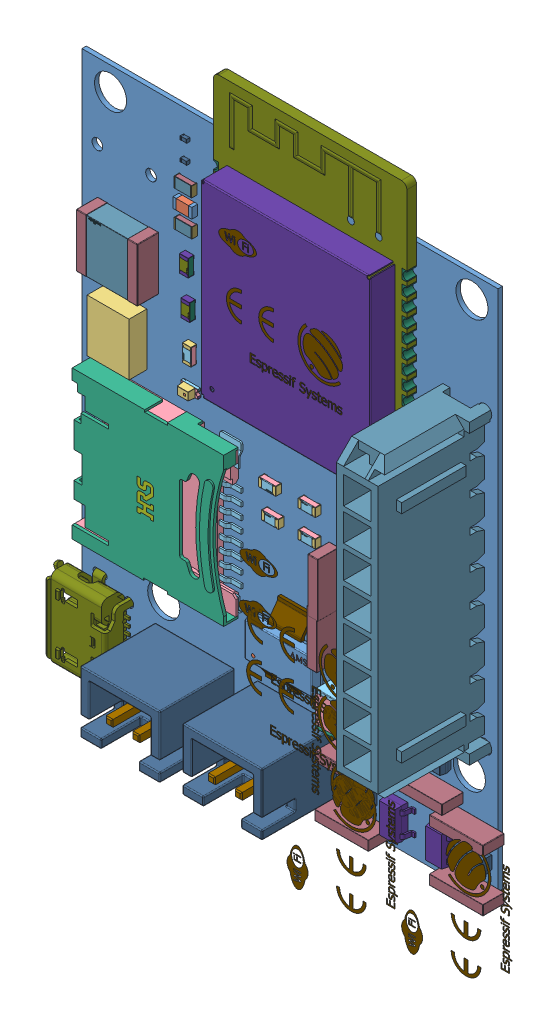
SolidWorks assembly PCB_F.step, configuration Default. Lengths in mm.
Overall size (45.18 58.57 13.33).
223 component instances, 63 part files, 0 mates.
Components (placement in the parent):
- Board.step-1: Board.step [Default] at origin size (38.73 49.78 0.41)
  - Open CASCADE STEP translator 7.5 1.1.1.step-1: Open CASCADE STEP translator 7.5 1.1.1.step [Default] at (0 0 -0.4115) size (38.73 49.78 0.41)
- D100.step-1: D100.step [Default] at origin size (1.6 0.8 0.9)
  - Diode_Lite-On_LTST-C190GKT_eec.step-1: Diode_Lite-On_LTST-C190GKT_eec.step [Default] at (150.229 50.673 0) x (-1 0 0) z (0 0 1) size (1.6 0.8 0.9)
    - 1.step-1: 1.step [Default] at (-0.1749 0.0038 0.001) size (0.2 0.2 0.05)
    - 2.step-1: 2.step [Default] at origin size (1.1 0.8 0.64)
    - 3.step-1: 3.step [Default] at origin size (1.6 0.8 0.28)
    - 4.step-1: 4.step [Default] at origin size (1.6 0.8 0.24)
    - Lite-On Logo Adjustable.step-1: Lite-On Logo Adjustable.step [Default] at (-0.9132 -0.3001 -1.9175) x (1 0 0) z (0 -1 0) size (0.21 0.05 0.1)
    - 5.step-1: 5.step [Default] at origin size (1.6 0.7 0.24)
    - 6.step-1: 6.step [Default] at origin size (1.6 0.15 0.24)
- J202.step-1: J202.step [Default] at origin size (7.4 5.75 10.4)
  - Conn_JST_B2B-XH-A_LF_SN_eec.step-1: Conn_JST_B2B-XH-A_LF_SN_eec.step [Default] at (160.02 27.305 0) x (-1 0 0) z (0 0 1) size (7.4 5.75 10.4)
    - 1-0.step-1: 1-0.step [Default] at (0 0.025 0) x (-1 0 0) z (0 1 0) size (7.4 10.4 5.75)
      - 1-1.step-1: 1-1.step [Default] at origin size (3.14 10.2 0.64)
      - B2B-XH-A.step-1: B2B-XH-A.step [Default] at origin size (7.4 7 5.75)
      - JST Logo adjustable.step-1: JST Logo adjustable.step [Default] at (-1.7267 5.5034 2.841) size (0.85 2.3 0.01)
- R103.step-1: R103.step [Default] at origin size (1.65 0.95 0.5)
  - 6298187712.step-1: 6298187712.step [Default] at (149.875 63.627 0) x (1 0 0) z (0 0 1) size (1.65 0.95 0.5)
    - Terminal.step-1: Terminal.step [Default] at (-0.825 -0.475 0) size (0.1 0.95 0.5)
      - Open CASCADE STEP translator 6.8 3.2.1.step-1: Open CASCADE STEP translator 6.8 3.2.1.step [Default] at origin size (0.1 0.95 0.5)
    - Terminal.step-2: Terminal.step [Default] at (0.825 0.475 0) x (-1 0 0) z (0 0 1) size (0.1 0.95 0.5)
      - Open CASCADE STEP translator 6.8 3.2.1.step-1: Open CASCADE STEP translator 6.8 3.2.1.step [Default] at origin size (0.1 0.95 0.5)
    - Mid_Body.step-1: Mid_Body.step [Default] at (-0.825 -0.475 0) size (1.55 0.95 0.4)
    - Mark.step-1: Mark.step [Default] at (-0.725 -0.475 0.45) size (1.45 0.95 0.05)
- R300.step-1: R300.step [Default] at origin size (1.6 0.8 0.56)
  - Res_Panasonic_Electronic_Components_ERA-3ARB202V_eec.step-1: Res_Panasonic_Electronic_Components_ERA-3ARB202V_eec.step [Default] at (165.9526 38.227 -0.4115) x (1 0 0) z (0 0 -1) size (1.6 0.8 0.56)
    - 1-2.step-1: 1-2.step [Default] at origin size (1.52 0.8 0.47)
    - 2-3.step-1: 2-3.step [Default] at origin size (1.08 0.8 0.04)
    - 3-4.step-1: 3-4.step [Default] at origin size (1.6 0.8 0.55)
    - Panasonic Logo.step-1: Panasonic Logo.step [Default] at (-0.1032 0.2046 0.451) size (0.41 0.06 0.11)
- R112.step-1: R112.step [Default] at origin size (1.75 0.95 0.55)
  - 6734516656.step-1: 6734516656.step [Default] at (149.135 65.278 0) size (0.3 0.95 0.55)
    - Extruded.step-1: Extruded.step [Default] at origin size (0.3 0.95 0.55)
  - 6734516656.step-2: 6734516656.step [Default] at (150.585 65.278 0) size (0.3 0.95 0.55)
    - Extruded.step-1: Extruded.step [Default] at origin size (0.3 0.95 0.55)
  - 6734516416.step-1: 6734516416.step [Default] at (149.86 65.278 0) size (1.15 0.95 0.55)
    - Extruded-5.step-1: Extruded-5.step [Default] at origin size (1.15 0.95 0.55)
- R111.step-1: R111.step [Default] at origin size (0.8 1.6 0.56)
  - Res_Panasonic_Electronic_Components_ERA-3ARB202V_eec.step-1: Res_Panasonic_Electronic_Components_ERA-3ARB202V_eec.step [Default] at (150.114 57.15 0) x (0 -1 0) z (0 0 1) size (1.6 0.8 0.56)
    - 1-2.step-1: 1-2.step [Default] at origin size (1.52 0.8 0.47)
    - 2-3.step-1: 2-3.step [Default] at origin size (1.08 0.8 0.04)
    - 3-4.step-1: 3-4.step [Default] at origin size (1.6 0.8 0.55)
    - Panasonic Logo.step-1: Panasonic Logo.step [Default] at (-0.1032 0.2046 0.451) size (0.41 0.06 0.11)
- R110.step-1: R110.step [Default] at origin size (0.8 1.6 0.56)
  - Res_Panasonic_Electronic_Components_ERA-3ARB202V_eec.step-1: Res_Panasonic_Electronic_Components_ERA-3ARB202V_eec.step [Default] at (149.987 60.6696 0) x (0 -1 0) z (0 0 1) size (1.6 0.8 0.56)
    - 1-2.step-1: 1-2.step [Default] at origin size (1.52 0.8 0.47)
    - 2-3.step-1: 2-3.step [Default] at origin size (1.08 0.8 0.04)
    - 3-4.step-1: 3-4.step [Default] at origin size (1.6 0.8 0.55)
    - Panasonic Logo.step-1: Panasonic Logo.step [Default] at (-0.1032 0.2046 0.451) size (0.41 0.06 0.11)
- R109.step-1: R109.step [Default] at origin size (1.6 0.8 0.56)
  - Res_Panasonic_ERJ-3GEYJ102V_eec.step-1: Res_Panasonic_ERJ-3GEYJ102V_eec.step [Default] at (157.988 44.196 0) x (1 0 0) z (0 0 1) size (1.6 0.8 0.56)
    - Pieza60.step-1: Pieza60.step [Default] at origin size (1.6 0.8 0.54)
    - Pieza63.step-1: Pieza63.step [Default] at (-0.65 -0.4 0.26) x (1 0 0) z (0 -1 0) size (1.5 0.44 0.8)
    - Pieza64.step-1: Pieza64.step [Default] at (0 -0.4 0.26) x (1 0 0) z (0 -1 0) size (1 0.06 0.8)
    - Pieza65.step-1: Pieza65.step [Default] at (-0.5 -0.4 0.55) x (-1 0 0) z (0 0 1) size (0.55 0.09 0.02)
- R108.step-1: R108.step [Default] at origin size (0.8 1.6 0.56)
  - Res_Panasonic_ERJ-3GEYJ102V_eec.step-1: Res_Panasonic_ERJ-3GEYJ102V_eec.step [Default] at (150.241 53.6051 0) x (0 1 0) z (0 0 1) size (1.6 0.8 0.56)
    - Pieza60.step-1: Pieza60.step [Default] at origin size (1.6 0.8 0.54)
    - Pieza63.step-1: Pieza63.step [Default] at (-0.65 -0.4 0.26) x (1 0 0) z (0 -1 0) size (1.5 0.44 0.8)
    - Pieza64.step-1: Pieza64.step [Default] at (0 -0.4 0.26) x (1 0 0) z (0 -1 0) size (1 0.06 0.8)
    - Pieza65.step-1: Pieza65.step [Default] at (-0.5 -0.4 0.55) x (-1 0 0) z (0 0 1) size (0.55 0.09 0.02)
- R107.step-1: R107.step [Default] at origin size (1.6 0.8 0.56)
  - Res_Panasonic_ERJ-3GEYJ102V_eec.step-1: Res_Panasonic_ERJ-3GEYJ102V_eec.step [Default] at (161.417 44.323 0) x (1 0 0) z (0 0 1) size (1.6 0.8 0.56)
    - Pieza60.step-1: Pieza60.step [Default] at origin size (1.6 0.8 0.54)
    - Pieza63.step-1: Pieza63.step [Default] at (-0.65 -0.4 0.26) x (1 0 0) z (0 -1 0) size (1.5 0.44 0.8)
    - Pieza64.step-1: Pieza64.step [Default] at (0 -0.4 0.26) x (1 0 0) z (0 -1 0) size (1 0.06 0.8)
    - Pieza65.step-1: Pieza65.step [Default] at (-0.5 -0.4 0.55) x (-1 0 0) z (0 0 1) size (0.55 0.09 0.02)
- R106.step-1: R106.step [Default] at origin size (1.6 0.8 0.56)
  - Res_Panasonic_ERJ-3GEYJ102V_eec.step-1: Res_Panasonic_ERJ-3GEYJ102V_eec.step [Default] at (161.417 46.863 0) x (1 0 0) z (0 0 1) size (1.6 0.8 0.56)
    - Pieza60.step-1: Pieza60.step [Default] at origin size (1.6 0.8 0.54)
    - Pieza63.step-1: Pieza63.step [Default] at (-0.65 -0.4 0.26) x (1 0 0) z (0 -1 0) size (1.5 0.44 0.8)
    - Pieza64.step-1: Pieza64.step [Default] at (0 -0.4 0.26) x (1 0 0) z (0 -1 0) size (1 0.06 0.8)
    - Pieza65.step-1: Pieza65.step [Default] at (-0.5 -0.4 0.55) x (-1 0 0) z (0 0 1) size (0.55 0.09 0.02)
- R105.step-1: R105.step [Default] at origin size (1.6 0.8 0.56)
  - Res_Panasonic_ERJ-3GEYJ102V_eec.step-1: Res_Panasonic_ERJ-3GEYJ102V_eec.step [Default] at (157.734 46.736 0) x (-1 0 0) z (0 0 1) size (1.6 0.8 0.56)
    - Pieza60.step-1: Pieza60.step [Default] at origin size (1.6 0.8 0.54)
    - Pieza63.step-1: Pieza63.step [Default] at (-0.65 -0.4 0.26) x (1 0 0) z (0 -1 0) size (1.5 0.44 0.8)
    - Pieza64.step-1: Pieza64.step [Default] at (0 -0.4 0.26) x (1 0 0) z (0 -1 0) size (1 0.06 0.8)
    - Pieza65.step-1: Pieza65.step [Default] at (-0.5 -0.4 0.55) x (-1 0 0) z (0 0 1) size (0.55 0.09 0.02)
- R104.step-1: R104.step [Default] at origin size (1.65 0.95 0.5)
  - 6298187712.step-1: 6298187712.step [Default] at (149.845 66.929 0) x (1 0 0) z (0 0 1) size (1.65 0.95 0.5)
    - Terminal.step-1: Terminal.step [Default] at (-0.825 -0.475 0) size (0.1 0.95 0.5)
      - Open CASCADE STEP translator 6.8 3.2.1.step-1: Open CASCADE STEP translator 6.8 3.2.1.step [Default] at origin size (0.1 0.95 0.5)
    - Terminal.step-2: Terminal.step [Default] at (0.825 0.475 0) x (-1 0 0) z (0 0 1) size (0.1 0.95 0.5)
      - Open CASCADE STEP translator 6.8 3.2.1.step-1: Open CASCADE STEP translator 6.8 3.2.1.step [Default] at origin size (0.1 0.95 0.5)
    - Mid_Body.step-1: Mid_Body.step [Default] at (-0.825 -0.475 0) size (1.55 0.95 0.4)
    - Mark.step-1: Mark.step [Default] at (-0.725 -0.475 0.45) size (1.45 0.95 0.05)
- R100.step-1: R100.step [Default] at origin size (1.65 0.95 0.5)
  - 6605284272.step-1: 6605284272.step [Default] at (169.784 48.641 0) x (-1 0 0) z (0 0 1) size (1.65 0.95 0.5)
    - Terminal-1.step-1: Terminal-1.step [Default] at (-0.825 -0.475 0) size (0.1 0.95 0.5)
      - Open CASCADE STEP translator 6.8 3.2.1-6.step-1: Open CASCADE STEP translator 6.8 3.2.1-6.step [Default] at origin size (0.1 0.95 0.5)
    - Terminal-1.step-2: Terminal-1.step [Default] at (0.825 0.475 0) x (-1 0 0) z (0 0 1) size (0.1 0.95 0.5)
      - Open CASCADE STEP translator 6.8 3.2.1-6.step-1: Open CASCADE STEP translator 6.8 3.2.1-6.step [Default] at origin size (0.1 0.95 0.5)
    - Mid_Body-7.step-1: Mid_Body-7.step [Default] at (-0.825 -0.475 0) size (1.55 0.95 0.4)
    - Mark-8.step-1: Mark-8.step [Default] at (-0.725 -0.475 0.45) size (1.45 0.95 0.05)
- C302.step-1: C302.step [Default] at origin size (0.6 0.32 0.32)
  - Cap_Murata_GRM155R71C104KA88D_eec.step-1: Cap_Murata_GRM155R71C104KA88D_eec.step [Default] at (159.62 38.354 -0.4115) x (-1 0 0) z (0 0 -1) size (0.6 0.32 0.32)
- C301.step-1: C301.step [Default] at origin size (0.32 0.6 0.32)
  - Cap_Murata_GRM155R71C104KA88D_eec.step-1: Cap_Murata_GRM155R71C104KA88D_eec.step [Default] at (169.037 38.354 -0.4115) x (0 -1 0) z (0 0 -1) size (0.6 0.32 0.32)
- C300.step-1: C300.step [Default] at origin size (1.77 1.01 0.91)
  - 6734513776.step-1: 6734513776.step [Default] at (162.433 38.227 -1.3215) size (1.27 1.01 0.91)
    - Extruded-9.step-1: Extruded-9.step [Default] at origin size (1.27 1.01 0.91)
  - 6734513616.step-1: 6734513616.step [Default] at (161.673 38.227 -1.3215) size (0.25 1.01 0.91)
    - Extruded-10.step-1: Extruded-10.step [Default] at origin size (0.25 1.01 0.91)
  - 6734513616.step-2: 6734513616.step [Default] at (163.193 38.227 -1.3215) size (0.25 1.01 0.91)
    - Extruded-10.step-1: Extruded-10.step [Default] at origin size (0.25 1.01 0.91)
- C103.step-1: C103.step [Default] at origin size (0.6 0.32 0.32)
  - Cap_Murata_GRM155R71C104KA88D_eec.step-1: Cap_Murata_GRM155R71C104KA88D_eec.step [Default] at (149.733 68.834 0) x (1 0 0) z (0 0 1) size (0.6 0.32 0.32)
- C102.step-1: C102.step [Default] at origin size (5.7 5 2)
  - Cap_Murata_GRM55D7U2H333JW31K_eec.step-1: Cap_Murata_GRM55D7U2H333JW31K_eec.step [Default] at (144.272 59.182 0) x (-1 0 0) z (0 0 1) size (5.7 5 2)
    - Terminals.step-1: Terminals.step [Default] at origin size (5.7 5 2)
    - Center.step-1: Center.step [Default] at origin size (3.85 4.95 1.95)
    - Murata.step-1: Murata.step [Default] at origin size (1.17 0.26 0)
- C101.step-1: C101.step [Default] at origin size (0.6 0.32 0.32)
  - Cap_Murata_GRM155R71C104KA88D_eec.step-1: Cap_Murata_GRM155R71C104KA88D_eec.step [Default] at (149.733 70.612 0) x (1 0 0) z (0 0 1) size (0.6 0.32 0.32)
- J201.step-1: J201.step [Default] at origin size (5.4 8.2 3.3)
  - 1050170001.step-1: 1050170001.step [Default] at (141.8522 27.9402 1.1978) x (0 -1 0) z (-1 0 0) size (8.2 3.3 5.4)
    - Open CASCADE STEP translator 7.5 1.22.1.1.step-1: Open CASCADE STEP translator 7.5 1.22.1.1.step [Default] at origin size (8.2 3.3 5.4)
    - Open CASCADE STEP translator 7.5 1.22.1.2.step-1: Open CASCADE STEP translator 7.5 1.22.1.2.step [Default] at origin
- J200.step-1: J200.step [Default] at origin size (7.4 5.75 10.4)
  - Conn_JST_B2B-XH-A_LF_SN_eec.step-1: Conn_JST_B2B-XH-A_LF_SN_eec.step [Default] at (150.495 27.178 0) x (-1 0 0) z (0 0 1) size (7.4 5.75 10.4)
    - 1-0.step-1: 1-0.step [Default] at (0 0.025 0) x (-1 0 0) z (0 1 0) size (7.4 10.4 5.75)
      - 1-1.step-1: 1-1.step [Default] at origin size (3.14 10.2 0.64)
      - B2B-XH-A.step-1: B2B-XH-A.step [Default] at origin size (7.4 7 5.75)
      - JST Logo adjustable.step-1: JST Logo adjustable.step [Default] at (-1.7267 5.5034 2.841) size (0.85 2.3 0.01)
- U202.step-1: U202.step [Default] at origin size (2.8 2.9 1.3)
  - 6605298272.step-1: 6605298272.step [Default] at (169.672 26.035 0) x (-1 0 0) z (0 1 0) size (2.8 1.3 2.9)
- U201.step-1: U201.step [Default] at origin size (6.51 7.05 1.8)
  - IC_Advanced_Monolithic_Systems_AMS1117-3_3_eec.step-1: IC_Advanced_Monolithic_Systems_AMS1117-3_3_eec.step [Default] at (160.02 34.671 0) x (0 1 0) z (0 0 1) size (7.05 6.51 1.8)
    - 2-11.step-1: 2-11.step [Default] x (1 0 0) z (0 -1 0) size (7.05 1.2 5.34)
      - Open CASCADE STEP translator 7.5 1.25.1.2.1.step-1: Open CASCADE STEP translator 7.5 1.25.1.2.1.step [Default] at origin size (7.05 1.2 5.34)
      - Open CASCADE STEP translator 7.5 1.25.1.2.2.step-1: Open CASCADE STEP translator 7.5 1.25.1.2.2.step [Default] at origin
    - 1-12.step-1: 1-12.step [Default] at (0 0 0.74) x (0 1 0) z (0 0 1) size (6.51 3.5 1.06)
    - Notch 2.step-1: Notch 2.step [Default] at (-0.7251 1.7063 1.701) size (2.3 5.16 0.1)
- U200.step-1: U200.step [Default] at origin size (2.8 2.9 1.3)
  - 6605298272.step-1: 6605298272.step [Default] at (173.99 26.162 0) x (-1 0 0) z (0 1 0) size (2.8 1.3 2.9)
- U100.step-1: U100.step [Default] at origin size (3.9 4.9 1.65)
  - 6734518816.step-1: 6734518816.step [Default] at (144.145 52.578 0.1) size (3.9 4.9 1.65)
    - Extruded-13.step-1: Extruded-13.step [Default] at origin size (3.9 4.9 1.65)
- SD100.step-1: SD100.step [Default] at origin size (14.1 13.8 2.13)
  - Conn_HIROSE_DM3CS-SF_eec.step-1: Conn_HIROSE_DM3CS-SF_eec.step [Default] at (148.082 41.783 0) x (0 1 0) z (0 0 1) size (13.8 14.1 2.13)
    - DM3CS-SF.step-1: DM3CS-SF.step [Default] at (-224.49 -126.3634 0.025) size (13.4 14.1 1.71)
    - Pieza12.step-1: Pieza12.step [Default] at (-4.9 -6.9139 0.4322) x (0 -1 0) z (-1 0 0) size (13.6 1.46 13.8)
    - Pieza13.step-1: Pieza13.step [Default] at (-7.2639 -7.4211 1.98) size (13.8 14.1 1.96)
    - Pieza14.step-1: Pieza14.step [Default] at (-0.3875 0.3409 1.98) size (2.92 1.53 0)
- R201.step-1: R201.step [Default] at origin size (3.25 1.65 0.7)
  - 6734515616.step-1: 6734515616.step [Default] at (169.926 37.973 0) size (2.25 1.65 0.7)
    - Extruded-14.step-1: Extruded-14.step [Default] at origin size (2.25 1.65 0.7)
  - 6734515456.step-1: 6734515456.step [Default] at (168.551 37.973 0) size (0.5 1.65 0.7)
    - Extruded-15.step-1: Extruded-15.step [Default] at origin size (0.5 1.65 0.7)
  - 6734515456.step-2: 6734515456.step [Default] at (171.301 37.973 0) size (0.5 1.65 0.7)
    - Extruded-15.step-1: Extruded-15.step [Default] at origin size (0.5 1.65 0.7)
- R200.step-1: R200.step [Default] at origin size (1.65 0.95 0.5)
  - 6605284272.step-1: 6605284272.step [Default] at (169.276 30.734 0) x (-1 0 0) z (0 0 1) size (1.65 0.95 0.5)
    - Terminal-1.step-1: Terminal-1.step [Default] at (-0.825 -0.475 0) size (0.1 0.95 0.5)
      - Open CASCADE STEP translator 6.8 3.2.1-6.step-1: Open CASCADE STEP translator 6.8 3.2.1-6.step [Default] at origin size (0.1 0.95 0.5)
    - Terminal-1.step-2: Terminal-1.step [Default] at (0.825 0.475 0) x (-1 0 0) z (0 0 1) size (0.1 0.95 0.5)
      - Open CASCADE STEP translator 6.8 3.2.1-6.step-1: Open CASCADE STEP translator 6.8 3.2.1-6.step [Default] at origin size (0.1 0.95 0.5)
    - Mid_Body-7.step-1: Mid_Body-7.step [Default] at (-0.825 -0.475 0) size (1.55 0.95 0.4)
    - Mark-8.step-1: Mark-8.step [Default] at (-0.725 -0.475 0.45) size (1.45 0.95 0.05)
- Q200.step-1: Q200.step [Default] at origin size (2.92 2.37 1.12)
  - 6605285552.step-1: 6605285552.step [Default] at (169.611 34.333 0) x (0 -1 0) z (0 0 1) size (2.37 2.92 1.12)
    - Body.step-1: Body.step [Default] at origin size (1.3 2.92 1.06)
    - PinsArrayL.step-1: PinsArrayL.step [Default] at origin size (0.54 2.33 0.61)
    - FilletPinR.step-1: FilletPinR.step [Default] at origin size (0.54 0.43 0.61)
- P100.step-1: P100.step [Default] at origin size (5.57 27.65 13.08)
  - 66200811122.step-1: 66200811122.step [Default] at (175.7691 48.9044 4.98) x (0 1 0) z (-1 0 0) size (27.65 13.08 5.57)
    - 6620xx11122_PIN.step-1: 6620xx11122_PIN.step [Default] at (-10.5 1.3806 0.255) x (-1 0 0) z (0 0 -1) size (0.64 10.1 0.9)
    - 6620xx11122_PIN.step-2: 6620xx11122_PIN.step [Default] at (-7.5 1.3806 0.255) size (0.64 10.1 0.9)
    - 6620xx11122_PIN.step-3: 6620xx11122_PIN.step [Default] at (-4.5 1.3806 0.255) x (-1 0 0) z (0 0 -1) size (0.64 10.1 0.9)
    - 6620xx11122_PIN.step-4: 6620xx11122_PIN.step [Default] at (-1.5 1.3806 0.255) size (0.64 10.1 0.9)
    - 6620xx11122_PIN.step-5: 6620xx11122_PIN.step [Default] at (1.5 1.3806 0.255) x (-1 0 0) z (0 0 -1) size (0.64 10.1 0.9)
    - 6620xx11122_PIN.step-6: 6620xx11122_PIN.step [Default] at (4.5 1.3806 0.255) size (0.64 10.1 0.9)
    - 6620xx11122_PIN.step-7: 6620xx11122_PIN.step [Default] at (7.5 1.3806 0.255) x (-1 0 0) z (0 0 -1) size (0.64 10.1 0.9)
    - 6620xx11122_PIN.step-8: 6620xx11122_PIN.step [Default] at (10.5 1.3806 0.255) size (0.64 10.1 0.9)
    - 66200811122-16.step-1: 66200811122-16.step [Default] at origin size (27.65 11 5.57)
- M100.step-1: M100.step [Default] at origin size (18 25.5 3.2)
  - UNK_Espressif_Systems_ESP32-WROOM-32_eec.step-1: UNK_Espressif_Systems_ESP32-WROOM-32_eec.step [Default] at (162.106 65.289 0) x (1 0 0) z (0 0 1) size (18 25.5 3.2)
    - 1-1-17.step-1: 1-1-17.step [Default] x (1 0 0) z (0 -1 0) size (18 3.2 25.5)
      - 2-18.step-1: 2-18.step [Default] at origin size (18 0.9 18.46)
      - 3-19.step-1: 3-19.step [Default] at origin size (18 0.95 25.5)
      - ESP32-WROOM-32D.step-1: ESP32-WROOM-32D.step [Default] at origin size (15.81 2.3 17.61)
      - Logo.step-1: Logo.step [Default] at (0.4143 -0.204 -1.2063) x (1 0 0) z (0 1 0) size (11.53 10.26 0.01)
      - 10.step-1: 10.step [Default] at (0 0.9 0) x (-1 0 0) z (0 1 0) size (3.23 0.64 0)
      - 11.step-1: 11.step [Default] at (0 0.9 0) x (-1 0 0) z (0 1 0) size (0.34 2.67 0)
- Cam300.step-1: Cam300.step [Default] at origin size (18.6 6.6 2.05)
  - 524352471.step-1: 524352471.step [Default] at (163.4141 41.4938 -0.4615) x (1 0 0) z (0 1 0) size (18.6 2.05 6.6)
    - Open CASCADE STEP translator 7.5 1.34.1.1.step-1: Open CASCADE STEP translator 7.5 1.34.1.1.step [Default] at origin size (18.6 2.05 6.6)
    - Open CASCADE STEP translator 7.5 1.34.1.2.step-1: Open CASCADE STEP translator 7.5 1.34.1.2.step [Default] at origin
- C207.step-1: C207.step [Default] at origin size (10.26 11.53 4.3)
  - Cap_Murata_GRM188R60J106KE47D_eec.step-1: Cap_Murata_GRM188R60J106KE47D_eec.step [Default] at (172.974 32.639 0) x (0 -1 0) z (0 0 1) size (11.53 10.26 4.3)
    - Terminals.step-1: Terminals.step [Default] at origin size (5.7 5 2)
    - Body.step-1: Body.step [Default] at origin size (1.3 2.92 1.06)
    - Logo.step-1: Logo.step [Default] at (-0.2332 0.5956 0.9) size (11.53 10.26 0.01)
- C206.step-1: C206.step [Default] at origin size (0.6 0.32 0.32)
  - Cap_Murata_GRM155R71C104KA88D_eec.step-1: Cap_Murata_GRM155R71C104KA88D_eec.step [Default] at (169.526 29.083 0) x (1 0 0) z (0 0 1) size (0.6 0.32 0.32)
- C205.step-1: C205.step [Default] at origin size (10.26 11.53 4.3)
  - Cap_Murata_GRM188R60J106KE47D_eec.step-1: Cap_Murata_GRM188R60J106KE47D_eec.step [Default] at (166.116 26.3289 0) x (0 1 0) z (0 0 1) size (11.53 10.26 4.3)
    - Terminals.step-1: Terminals.step [Default] at origin size (5.7 5 2)
    - Body.step-1: Body.step [Default] at origin size (1.3 2.92 1.06)
    - Logo.step-1: Logo.step [Default] at (-0.2332 0.5956 0.9) size (11.53 10.26 0.01)
- C204.step-1: C204.step [Default] at origin size (11.53 10.26 4.3)
  - Cap_Murata_GRM188R60J106KE47D_eec.step-1: Cap_Murata_GRM188R60J106KE47D_eec.step [Default] at (165.8221 42.164 0) x (1 0 0) z (0 0 1) size (11.53 10.26 4.3)
    - Terminals.step-1: Terminals.step [Default] at origin size (5.7 5 2)
    - Body.step-1: Body.step [Default] at origin size (1.3 2.92 1.06)
    - Logo.step-1: Logo.step [Default] at (-0.2332 0.5956 0.9) size (11.53 10.26 0.01)
- C203.step-1: C203.step [Default] at origin size (2.5 3.2 2.7)
  - Cap_Murata_GRM32ER60J107ME20L_eec.step-1: Cap_Murata_GRM32ER60J107ME20L_eec.step [Default] at (165.608 33.275 0) x (0 1 0) z (0 0 1) size (2.6 2.5 2.7)
  - Cap_Murata_GRM32ER60J107ME20L_eec-20.step-1: Cap_Murata_GRM32ER60J107ME20L_eec-20.step [Default] at (165.608 33.275 0) x (0 1 0) z (0 0 1) size (0.3 2.5 2.7)
  - Cap_Murata_GRM32ER60J107ME20L_eec-21.step-1: Cap_Murata_GRM32ER60J107ME20L_eec-21.step [Default] at (165.608 33.275 0) x (0 1 0) z (0 0 1) size (0.3 2.5 2.7)
- C202.step-1: C202.step [Default] at origin size (11.53 10.26 4.3)
  - Cap_Murata_GRM188R60J106KE47D_eec.step-1: Cap_Murata_GRM188R60J106KE47D_eec.step [Default] at (165.735 37.973 0) x (1 0 0) z (0 0 1) size (11.53 10.26 4.3)
    - Terminals.step-1: Terminals.step [Default] at origin size (5.7 5 2)
    - Body.step-1: Body.step [Default] at origin size (1.3 2.92 1.06)
    - Logo.step-1: Logo.step [Default] at (-0.2332 0.5956 0.9) size (11.53 10.26 0.01)
- C201.step-1: C201.step [Default] at origin size (0.6 0.32 0.32)
  - Cap_Murata_GRM155R71C104KA88D_eec.step-1: Cap_Murata_GRM155R71C104KA88D_eec.step [Default] at (174.244 29.083 0) x (-1 0 0) z (0 0 1) size (0.6 0.32 0.32)
- C200.step-1: C200.step [Default] at origin size (10.26 11.53 4.3)
  - Cap_Murata_GRM188R60J106KE47D_eec.step-1: Cap_Murata_GRM188R60J106KE47D_eec.step [Default] at (176.784 26.4559 0) x (0 1 0) z (0 0 1) size (11.53 10.26 4.3)
    - Terminals.step-1: Terminals.step [Default] at origin size (5.7 5 2)
    - Body.step-1: Body.step [Default] at origin size (1.3 2.92 1.06)
    - Logo.step-1: Logo.step [Default] at (-0.2332 0.5956 0.9) size (11.53 10.26 0.01)
